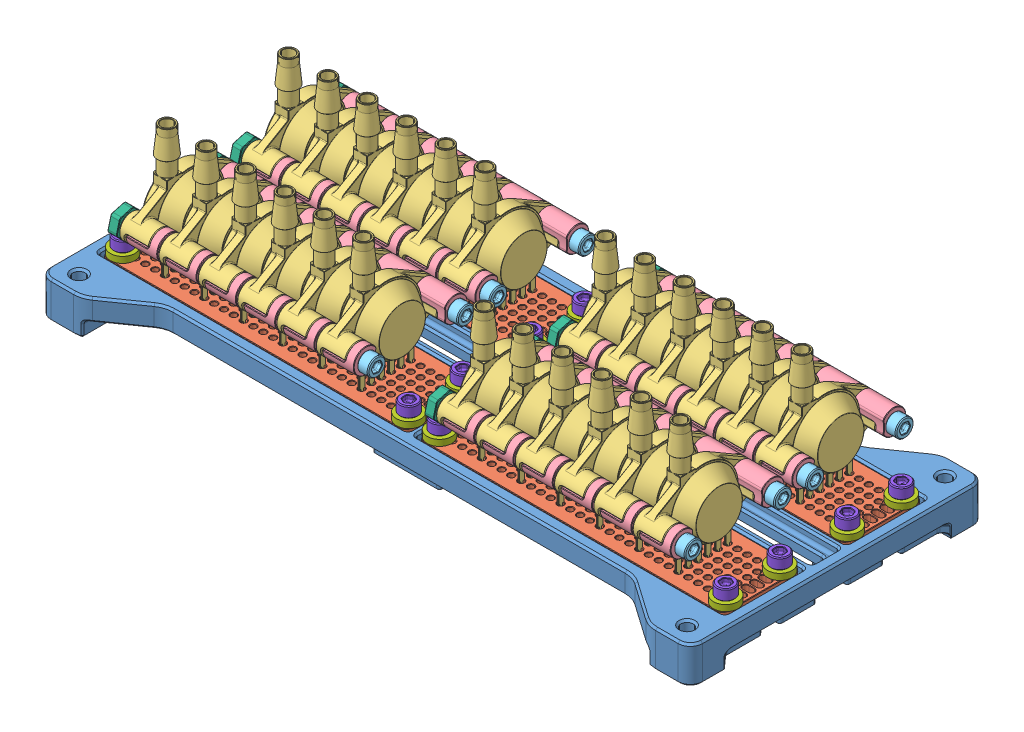
SolidWorks assembly AARL_QR_EL_PM-Pressure_Sensor_Mounting, configuration Default. Lengths in mm.
Overall size (169.39 41.14 76.2).
145 component instances, 8 part files, 124 mates.
Components (placement in the parent):
- AARL_QR_EL_PM_014-1: AARL_QR_EL_PM_014 [Default] at origin size (169.39 9.53 76.2)
- AARL_QR_EL_PA_000-Pressure_Sensor_Array-1: AARL_QR_EL_PA_000-Pressure_Sensor_Array [Default] at (-40.9575 4.1745 15.7163) size (78.74 37.75 32.61)
  - AARL_Puppy_18_03_01_009-1: AARL_Puppy_18_03_01_009 [Default] at origin size (78.74 2 20.32)
  - AARL_Puppy_18_03_01_002-MPX5700GP-1: AARL_Puppy_18_03_01_002-MPX5700GP [Default] at (-30.47 12.9995 0) x (0 0 -1) z (1 0 0) size (29.5 37.75 8.49)
  - AARL_Puppy_18_03_01_002-MPX5700GP-2: AARL_Puppy_18_03_01_002-MPX5700GP [Default] at (-20.31 12.9995 0) x (0 0 -1) z (1 0 0) size (29.5 37.75 8.49)
  - AARL_Puppy_18_03_01_002-MPX5700GP-3: AARL_Puppy_18_03_01_002-MPX5700GP [Default] at (-10.15 12.9995 0) x (0 0 -1) z (1 0 0) size (29.5 37.75 8.49)
  - AARL_Puppy_18_03_01_002-MPX5700GP-4: AARL_Puppy_18_03_01_002-MPX5700GP [Default] at (0.01 12.9995 0) x (0 0 -1) z (1 0 0) size (29.5 37.75 8.49)
  - AARL_Puppy_18_03_01_002-MPX5700GP-5: AARL_Puppy_18_03_01_002-MPX5700GP [Default] at (10.17 12.9995 0) x (0 0 -1) z (1 0 0) size (29.5 37.75 8.49)
  - AARL_Puppy_18_03_01_002-MPX5700GP-6: AARL_Puppy_18_03_01_002-MPX5700GP [Default] at (20.33 12.9995 0) x (0 0 -1) z (1 0 0) size (29.5 37.75 8.49)
  - AARL_Puppy_18_03_01_010-1: AARL_Puppy_18_03_01_010 [Default] at (-20.309 12.9995 11.555) x (0 1 0) z (0 0 1) size (6.35 8.16 5.84)
  - AARL_Puppy_18_03_01_010-2: AARL_Puppy_18_03_01_010 [Default] at (-20.309 12.9995 -11.555) x (0 -1 0) z (0 0 -1) size (6.35 8.16 5.84)
  - AARL_Puppy_18_03_01_010-3: AARL_Puppy_18_03_01_010 [Default] at (-10.149 12.9995 11.555) x (0 1 0) z (0 0 1) size (6.35 8.16 5.84)
  - AARL_Puppy_18_03_01_010-4: AARL_Puppy_18_03_01_010 [Default] at (0.011 12.9995 11.555) x (0 1 0) z (0 0 1) size (6.35 8.16 5.84)
  - AARL_Puppy_18_03_01_010-5: AARL_Puppy_18_03_01_010 [Default] at (10.171 12.9995 11.555) x (0 1 0) z (0 0 1) size (6.35 8.16 5.84)
  - AARL_Puppy_18_03_01_010-6: AARL_Puppy_18_03_01_010 [Default] at (20.331 12.9995 11.555) x (0 1 0) z (0 0 1) size (6.35 8.16 5.84)
  - AARL_Puppy_18_03_01_010-7: AARL_Puppy_18_03_01_010 [Default] at (30.491 12.9995 11.555) x (0 1 0) z (0 0 1) size (6.35 8.16 5.84)
  - AARL_Puppy_18_03_01_010-8: AARL_Puppy_18_03_01_010 [Default] at (-10.1485 12.9995 -11.555) x (0 -1 0) z (0 0 -1) size (6.35 8.16 5.84)
  - AARL_Puppy_18_03_01_010-9: AARL_Puppy_18_03_01_010 [Default] at (0.0115 12.9995 -11.555) x (0 -1 0) z (0 0 -1) size (6.35 8.16 5.84)
  - AARL_Puppy_18_03_01_010-10: AARL_Puppy_18_03_01_010 [Default] at (10.171 12.9995 -11.555) x (0 -1 0) z (0 0 -1) size (6.35 8.16 5.84)
  - AARL_Puppy_18_03_01_010-11: AARL_Puppy_18_03_01_010 [Default] at (20.331 12.9995 -11.555) x (0 -1 0) z (0 0 -1) size (6.35 8.16 5.84)
  - AARL_Puppy_18_03_01_010-12: AARL_Puppy_18_03_01_010 [Default] at (30.491 12.9995 -11.555) x (0 -1 0) z (0 0 -1) size (6.35 8.16 5.84)
  - AARL_Puppy_18_04_01_014-1: AARL_Puppy_18_04_01_014 [Default] at (33.3358 12.9995 11.555) x (0 -0.609481 -0.792801) z (0 0.792801 -0.609481) size (4.65 66.53 4.65)
  - AARL_Puppy_18_04_01_014-2: AARL_Puppy_18_04_01_014 [Default] at (33.3358 12.9995 -11.555) x (0 -0.609481 -0.792801) z (0 0.792801 -0.609481) size (4.65 66.53 4.65)
  - AARL_QR_HW_NU_002-1: AARL_QR_HW_NU_002 [Default] at (-31.6606 12.9995 11.555) x (0 0.703871 0.710328) z (0 -0.710328 0.703871) size (7.09 2.38 6.35)
  - AARL_QR_HW_NU_002-2: AARL_QR_HW_NU_002 [Default] at (-31.6606 12.9995 -11.555) x (0 0.703871 0.710328) z (0 -0.710328 0.703871) size (7.09 2.38 6.35)
- AARL_QR_EL_PA_000-Pressure_Sensor_Array-2: AARL_QR_EL_PA_000-Pressure_Sensor_Array [Default] at (-40.9575 4.1745 -15.7163) size (78.74 37.75 32.61)
  - AARL_Puppy_18_03_01_009-1: AARL_Puppy_18_03_01_009 [Default] at origin size (78.74 2 20.32)
  - AARL_Puppy_18_03_01_002-MPX5700GP-1: AARL_Puppy_18_03_01_002-MPX5700GP [Default] at (-30.47 12.9995 0) x (0 0 -1) z (1 0 0) size (29.5 37.75 8.49)
  - AARL_Puppy_18_03_01_002-MPX5700GP-2: AARL_Puppy_18_03_01_002-MPX5700GP [Default] at (-20.31 12.9995 0) x (0 0 -1) z (1 0 0) size (29.5 37.75 8.49)
  - AARL_Puppy_18_03_01_002-MPX5700GP-3: AARL_Puppy_18_03_01_002-MPX5700GP [Default] at (-10.15 12.9995 0) x (0 0 -1) z (1 0 0) size (29.5 37.75 8.49)
  - AARL_Puppy_18_03_01_002-MPX5700GP-4: AARL_Puppy_18_03_01_002-MPX5700GP [Default] at (0.01 12.9995 0) x (0 0 -1) z (1 0 0) size (29.5 37.75 8.49)
  - AARL_Puppy_18_03_01_002-MPX5700GP-5: AARL_Puppy_18_03_01_002-MPX5700GP [Default] at (10.17 12.9995 0) x (0 0 -1) z (1 0 0) size (29.5 37.75 8.49)
  - AARL_Puppy_18_03_01_002-MPX5700GP-6: AARL_Puppy_18_03_01_002-MPX5700GP [Default] at (20.33 12.9995 0) x (0 0 -1) z (1 0 0) size (29.5 37.75 8.49)
  - AARL_Puppy_18_03_01_010-1: AARL_Puppy_18_03_01_010 [Default] at (-20.309 12.9995 11.555) x (0 1 0) z (0 0 1) size (6.35 8.16 5.84)
  - AARL_Puppy_18_03_01_010-2: AARL_Puppy_18_03_01_010 [Default] at (-20.309 12.9995 -11.555) x (0 -1 0) z (0 0 -1) size (6.35 8.16 5.84)
  - AARL_Puppy_18_03_01_010-3: AARL_Puppy_18_03_01_010 [Default] at (-10.149 12.9995 11.555) x (0 1 0) z (0 0 1) size (6.35 8.16 5.84)
  - AARL_Puppy_18_03_01_010-4: AARL_Puppy_18_03_01_010 [Default] at (0.011 12.9995 11.555) x (0 1 0) z (0 0 1) size (6.35 8.16 5.84)
  - AARL_Puppy_18_03_01_010-5: AARL_Puppy_18_03_01_010 [Default] at (10.171 12.9995 11.555) x (0 1 0) z (0 0 1) size (6.35 8.16 5.84)
  - AARL_Puppy_18_03_01_010-6: AARL_Puppy_18_03_01_010 [Default] at (20.331 12.9995 11.555) x (0 1 0) z (0 0 1) size (6.35 8.16 5.84)
  - AARL_Puppy_18_03_01_010-7: AARL_Puppy_18_03_01_010 [Default] at (30.491 12.9995 11.555) x (0 1 0) z (0 0 1) size (6.35 8.16 5.84)
  - AARL_Puppy_18_03_01_010-8: AARL_Puppy_18_03_01_010 [Default] at (-10.1485 12.9995 -11.555) x (0 -1 0) z (0 0 -1) size (6.35 8.16 5.84)
  - AARL_Puppy_18_03_01_010-9: AARL_Puppy_18_03_01_010 [Default] at (0.0115 12.9995 -11.555) x (0 -1 0) z (0 0 -1) size (6.35 8.16 5.84)
  - AARL_Puppy_18_03_01_010-10: AARL_Puppy_18_03_01_010 [Default] at (10.171 12.9995 -11.555) x (0 -1 0) z (0 0 -1) size (6.35 8.16 5.84)
  - AARL_Puppy_18_03_01_010-11: AARL_Puppy_18_03_01_010 [Default] at (20.331 12.9995 -11.555) x (0 -1 0) z (0 0 -1) size (6.35 8.16 5.84)
  - AARL_Puppy_18_03_01_010-12: AARL_Puppy_18_03_01_010 [Default] at (30.491 12.9995 -11.555) x (0 -1 0) z (0 0 -1) size (6.35 8.16 5.84)
  - AARL_Puppy_18_04_01_014-1: AARL_Puppy_18_04_01_014 [Default] at (33.3358 12.9995 11.555) x (0 -0.609481 -0.792801) z (0 0.792801 -0.609481) size (4.65 66.53 4.65)
  - AARL_Puppy_18_04_01_014-2: AARL_Puppy_18_04_01_014 [Default] at (33.3358 12.9995 -11.555) x (0 -0.609481 -0.792801) z (0 0.792801 -0.609481) size (4.65 66.53 4.65)
  - AARL_QR_HW_NU_002-1: AARL_QR_HW_NU_002 [Default] at (-31.6606 12.9995 11.555) x (0 0.703871 0.710328) z (0 -0.710328 0.703871) size (7.09 2.38 6.35)
  - AARL_QR_HW_NU_002-2: AARL_QR_HW_NU_002 [Default] at (-31.6606 12.9995 -11.555) x (0 0.703871 0.710328) z (0 -0.710328 0.703871) size (7.09 2.38 6.35)
- AARL_QR_EL_PA_000-Pressure_Sensor_Array-3: AARL_QR_EL_PA_000-Pressure_Sensor_Array [Default] at (40.9575 4.1745 15.7163) size (78.74 37.75 32.61)
  - AARL_Puppy_18_03_01_009-1: AARL_Puppy_18_03_01_009 [Default] at origin size (78.74 2 20.32)
  - AARL_Puppy_18_03_01_002-MPX5700GP-1: AARL_Puppy_18_03_01_002-MPX5700GP [Default] at (-30.47 12.9995 0) x (0 0 -1) z (1 0 0) size (29.5 37.75 8.49)
  - AARL_Puppy_18_03_01_002-MPX5700GP-2: AARL_Puppy_18_03_01_002-MPX5700GP [Default] at (-20.31 12.9995 0) x (0 0 -1) z (1 0 0) size (29.5 37.75 8.49)
  - AARL_Puppy_18_03_01_002-MPX5700GP-3: AARL_Puppy_18_03_01_002-MPX5700GP [Default] at (-10.15 12.9995 0) x (0 0 -1) z (1 0 0) size (29.5 37.75 8.49)
  - AARL_Puppy_18_03_01_002-MPX5700GP-4: AARL_Puppy_18_03_01_002-MPX5700GP [Default] at (0.01 12.9995 0) x (0 0 -1) z (1 0 0) size (29.5 37.75 8.49)
  - AARL_Puppy_18_03_01_002-MPX5700GP-5: AARL_Puppy_18_03_01_002-MPX5700GP [Default] at (10.17 12.9995 0) x (0 0 -1) z (1 0 0) size (29.5 37.75 8.49)
  - AARL_Puppy_18_03_01_002-MPX5700GP-6: AARL_Puppy_18_03_01_002-MPX5700GP [Default] at (20.33 12.9995 0) x (0 0 -1) z (1 0 0) size (29.5 37.75 8.49)
  - AARL_Puppy_18_03_01_010-1: AARL_Puppy_18_03_01_010 [Default] at (-20.309 12.9995 11.555) x (0 1 0) z (0 0 1) size (6.35 8.16 5.84)
  - AARL_Puppy_18_03_01_010-2: AARL_Puppy_18_03_01_010 [Default] at (-20.309 12.9995 -11.555) x (0 -1 0) z (0 0 -1) size (6.35 8.16 5.84)
  - AARL_Puppy_18_03_01_010-3: AARL_Puppy_18_03_01_010 [Default] at (-10.149 12.9995 11.555) x (0 1 0) z (0 0 1) size (6.35 8.16 5.84)
  - AARL_Puppy_18_03_01_010-4: AARL_Puppy_18_03_01_010 [Default] at (0.011 12.9995 11.555) x (0 1 0) z (0 0 1) size (6.35 8.16 5.84)
  - AARL_Puppy_18_03_01_010-5: AARL_Puppy_18_03_01_010 [Default] at (10.171 12.9995 11.555) x (0 1 0) z (0 0 1) size (6.35 8.16 5.84)
  - AARL_Puppy_18_03_01_010-6: AARL_Puppy_18_03_01_010 [Default] at (20.331 12.9995 11.555) x (0 1 0) z (0 0 1) size (6.35 8.16 5.84)
  - AARL_Puppy_18_03_01_010-7: AARL_Puppy_18_03_01_010 [Default] at (30.491 12.9995 11.555) x (0 1 0) z (0 0 1) size (6.35 8.16 5.84)
  - AARL_Puppy_18_03_01_010-8: AARL_Puppy_18_03_01_010 [Default] at (-10.1485 12.9995 -11.555) x (0 -1 0) z (0 0 -1) size (6.35 8.16 5.84)
  - AARL_Puppy_18_03_01_010-9: AARL_Puppy_18_03_01_010 [Default] at (0.0115 12.9995 -11.555) x (0 -1 0) z (0 0 -1) size (6.35 8.16 5.84)
  - AARL_Puppy_18_03_01_010-10: AARL_Puppy_18_03_01_010 [Default] at (10.171 12.9995 -11.555) x (0 -1 0) z (0 0 -1) size (6.35 8.16 5.84)
  - AARL_Puppy_18_03_01_010-11: AARL_Puppy_18_03_01_010 [Default] at (20.331 12.9995 -11.555) x (0 -1 0) z (0 0 -1) size (6.35 8.16 5.84)
  - AARL_Puppy_18_03_01_010-12: AARL_Puppy_18_03_01_010 [Default] at (30.491 12.9995 -11.555) x (0 -1 0) z (0 0 -1) size (6.35 8.16 5.84)
  - AARL_Puppy_18_04_01_014-1: AARL_Puppy_18_04_01_014 [Default] at (33.3358 12.9995 11.555) x (0 -0.609481 -0.792801) z (0 0.792801 -0.609481) size (4.65 66.53 4.65)
  - AARL_Puppy_18_04_01_014-2: AARL_Puppy_18_04_01_014 [Default] at (33.3358 12.9995 -11.555) x (0 -0.609481 -0.792801) z (0 0.792801 -0.609481) size (4.65 66.53 4.65)
  - AARL_QR_HW_NU_002-1: AARL_QR_HW_NU_002 [Default] at (-31.6606 12.9995 11.555) x (0 0.703871 0.710328) z (0 -0.710328 0.703871) size (7.09 2.38 6.35)
  - AARL_QR_HW_NU_002-2: AARL_QR_HW_NU_002 [Default] at (-31.6606 12.9995 -11.555) x (0 0.703871 0.710328) z (0 -0.710328 0.703871) size (7.09 2.38 6.35)
- AARL_QR_EL_PA_000-Pressure_Sensor_Array-4: AARL_QR_EL_PA_000-Pressure_Sensor_Array [Default] at (40.9575 4.1745 -15.7163) size (78.74 37.75 32.61)
  - AARL_Puppy_18_03_01_009-1: AARL_Puppy_18_03_01_009 [Default] at origin size (78.74 2 20.32)
  - AARL_Puppy_18_03_01_002-MPX5700GP-1: AARL_Puppy_18_03_01_002-MPX5700GP [Default] at (-30.47 12.9995 0) x (0 0 -1) z (1 0 0) size (29.5 37.75 8.49)
  - AARL_Puppy_18_03_01_002-MPX5700GP-2: AARL_Puppy_18_03_01_002-MPX5700GP [Default] at (-20.31 12.9995 0) x (0 0 -1) z (1 0 0) size (29.5 37.75 8.49)
  - AARL_Puppy_18_03_01_002-MPX5700GP-3: AARL_Puppy_18_03_01_002-MPX5700GP [Default] at (-10.15 12.9995 0) x (0 0 -1) z (1 0 0) size (29.5 37.75 8.49)
  - AARL_Puppy_18_03_01_002-MPX5700GP-4: AARL_Puppy_18_03_01_002-MPX5700GP [Default] at (0.01 12.9995 0) x (0 0 -1) z (1 0 0) size (29.5 37.75 8.49)
  - AARL_Puppy_18_03_01_002-MPX5700GP-5: AARL_Puppy_18_03_01_002-MPX5700GP [Default] at (10.17 12.9995 0) x (0 0 -1) z (1 0 0) size (29.5 37.75 8.49)
  - AARL_Puppy_18_03_01_002-MPX5700GP-6: AARL_Puppy_18_03_01_002-MPX5700GP [Default] at (20.33 12.9995 0) x (0 0 -1) z (1 0 0) size (29.5 37.75 8.49)
  - AARL_Puppy_18_03_01_010-1: AARL_Puppy_18_03_01_010 [Default] at (-20.309 12.9995 11.555) x (0 1 0) z (0 0 1) size (6.35 8.16 5.84)
  - AARL_Puppy_18_03_01_010-2: AARL_Puppy_18_03_01_010 [Default] at (-20.309 12.9995 -11.555) x (0 -1 0) z (0 0 -1) size (6.35 8.16 5.84)
  - AARL_Puppy_18_03_01_010-3: AARL_Puppy_18_03_01_010 [Default] at (-10.149 12.9995 11.555) x (0 1 0) z (0 0 1) size (6.35 8.16 5.84)
  - AARL_Puppy_18_03_01_010-4: AARL_Puppy_18_03_01_010 [Default] at (0.011 12.9995 11.555) x (0 1 0) z (0 0 1) size (6.35 8.16 5.84)
  - AARL_Puppy_18_03_01_010-5: AARL_Puppy_18_03_01_010 [Default] at (10.171 12.9995 11.555) x (0 1 0) z (0 0 1) size (6.35 8.16 5.84)
  - AARL_Puppy_18_03_01_010-6: AARL_Puppy_18_03_01_010 [Default] at (20.331 12.9995 11.555) x (0 1 0) z (0 0 1) size (6.35 8.16 5.84)
  - AARL_Puppy_18_03_01_010-7: AARL_Puppy_18_03_01_010 [Default] at (30.491 12.9995 11.555) x (0 1 0) z (0 0 1) size (6.35 8.16 5.84)
  - AARL_Puppy_18_03_01_010-8: AARL_Puppy_18_03_01_010 [Default] at (-10.1485 12.9995 -11.555) x (0 -1 0) z (0 0 -1) size (6.35 8.16 5.84)
  - AARL_Puppy_18_03_01_010-9: AARL_Puppy_18_03_01_010 [Default] at (0.0115 12.9995 -11.555) x (0 -1 0) z (0 0 -1) size (6.35 8.16 5.84)
  - AARL_Puppy_18_03_01_010-10: AARL_Puppy_18_03_01_010 [Default] at (10.171 12.9995 -11.555) x (0 -1 0) z (0 0 -1) size (6.35 8.16 5.84)
  - AARL_Puppy_18_03_01_010-11: AARL_Puppy_18_03_01_010 [Default] at (20.331 12.9995 -11.555) x (0 -1 0) z (0 0 -1) size (6.35 8.16 5.84)
  - AARL_Puppy_18_03_01_010-12: AARL_Puppy_18_03_01_010 [Default] at (30.491 12.9995 -11.555) x (0 -1 0) z (0 0 -1) size (6.35 8.16 5.84)
  - AARL_Puppy_18_04_01_014-1: AARL_Puppy_18_04_01_014 [Default] at (33.3358 12.9995 11.555) x (0 -0.609481 -0.792801) z (0 0.792801 -0.609481) size (4.65 66.53 4.65)
  - AARL_Puppy_18_04_01_014-2: AARL_Puppy_18_04_01_014 [Default] at (33.3358 12.9995 -11.555) x (0 -0.609481 -0.792801) z (0 0.792801 -0.609481) size (4.65 66.53 4.65)
  - AARL_QR_HW_NU_002-1: AARL_QR_HW_NU_002 [Default] at (-31.6606 12.9995 11.555) x (0 0.703871 0.710328) z (0 -0.710328 0.703871) size (7.09 2.38 6.35)
  - AARL_QR_HW_NU_002-2: AARL_QR_HW_NU_002 [Default] at (-31.6606 12.9995 -11.555) x (0 0.703871 0.710328) z (0 -0.710328 0.703871) size (7.09 2.38 6.35)
- AARL_QR_HW_NU_002-1: AARL_QR_HW_NU_002 [Default] at (77.9462 -1.1906 -22.7012) size (7.09 2.38 6.35)
- AARL_QR_HW_NU_002-2: AARL_QR_HW_NU_002 [Default] at (77.9462 -1.1906 -8.7312) x (0.5 0 -0.866025) z (0.866025 0 0.5) size (7.09 2.38 6.35)
- AARL_QR_HW_NU_002-3: AARL_QR_HW_NU_002 [Default] at (77.9462 -1.1906 8.7312) x (0.5 0 -0.866025) z (0.866025 0 0.5) size (7.09 2.38 6.35)
- AARL_QR_HW_NU_002-4: AARL_QR_HW_NU_002 [Default] at (77.9462 -1.1906 22.7012) x (-0.5 0 -0.866025) z (0.866025 0 -0.5) size (7.09 2.38 6.35)
- AARL_QR_HW_NU_002-5: AARL_QR_HW_NU_002 [Default] at (3.9688 -1.1906 -22.7012) x (-0.5 0 0.866025) z (-0.866025 0 -0.5) size (7.09 2.38 6.35)
- AARL_QR_HW_NU_002-6: AARL_QR_HW_NU_002 [Default] at (-3.9688 -1.1906 -22.7012) x (-0.5 0 0.866025) z (-0.866025 0 -0.5) size (7.09 2.38 6.35)
- AARL_QR_HW_NU_002-7: AARL_QR_HW_NU_002 [Default] at (3.9688 -1.1906 -8.7312) x (-0.5 0 0.866025) z (-0.866025 0 -0.5) size (7.09 2.38 6.35)
- AARL_QR_HW_NU_002-8: AARL_QR_HW_NU_002 [Default] at (-3.9688 -1.1906 -8.7312) x (-0.5 0 0.866025) z (-0.866025 0 -0.5) size (7.09 2.38 6.35)
- AARL_QR_HW_NU_002-9: AARL_QR_HW_NU_002 [Default] at (3.9688 -1.1906 8.7312) x (-0.5 0 0.866025) z (-0.866025 0 -0.5) size (7.09 2.38 6.35)
- AARL_QR_HW_NU_002-10: AARL_QR_HW_NU_002 [Default] at (-3.9688 -1.1906 8.7312) x (-0.5 0 0.866025) z (-0.866025 0 -0.5) size (7.09 2.38 6.35)
- AARL_QR_HW_NU_002-11: AARL_QR_HW_NU_002 [Default] at (3.9688 -1.1906 22.7012) size (7.09 2.38 6.35)
- AARL_QR_HW_NU_002-12: AARL_QR_HW_NU_002 [Default] at (-3.9688 -1.1906 22.7012) size (7.09 2.38 6.35)
- AARL_QR_HW_NU_002-13: AARL_QR_HW_NU_002 [Default] at (-77.9462 -1.1906 22.7012) x (0.5 0 -0.866025) z (0.866025 0 0.5) size (7.09 2.38 6.35)
- AARL_QR_HW_NU_002-14: AARL_QR_HW_NU_002 [Default] at (-77.9462 -1.1906 8.7312) x (0.5 0 -0.866025) z (0.866025 0 0.5) size (7.09 2.38 6.35)
- AARL_QR_HW_NU_002-15: AARL_QR_HW_NU_002 [Default] at (-77.9462 -1.1906 -8.7312) x (0.5 0 -0.866025) z (0.866025 0 0.5) size (7.09 2.38 6.35)
- AARL_QR_HW_NU_002-16: AARL_QR_HW_NU_002 [Default] at (-77.9462 -1.1906 -22.7012) x (0.5 0 -0.866025) z (0.866025 0 0.5) size (7.09 2.38 6.35)
- AARL_QR_HW_WA_002-1: AARL_QR_HW_WA_002 [Default] at (77.9462 5.9677 22.7012) x (0.412963 0 0.910748) z (-0.910748 0 0.412963) size (6.35 1.59 6.35)
- AARL_QR_HW_WA_002-2: AARL_QR_HW_WA_002 [Default] at (3.9688 5.9677 8.7312) x (0.998043 0 0.062526) z (-0.062526 0 0.998043) size (6.35 1.59 6.35)
- AARL_QR_HW_WA_002-3: AARL_QR_HW_WA_002 [Default] at (77.9462 5.9677 8.7312) x (0.253018 0 0.967462) z (-0.967462 0 0.253018) size (6.35 1.59 6.35)
- AARL_QR_HW_WA_002-4: AARL_QR_HW_WA_002 [Default] at (3.9688 5.9677 22.7012) x (0.071525 0 0.997439) z (-0.997439 0 0.071525) size (6.35 1.59 6.35)
- AARL_QR_HW_WA_002-5: AARL_QR_HW_WA_002 [Default] at (-3.9688 5.9677 22.7012) x (0.996603 0 -0.082353) z (0.082353 0 0.996603) size (6.35 1.59 6.35)
- AARL_QR_HW_WA_002-6: AARL_QR_HW_WA_002 [Default] at (-3.9688 5.9677 8.7312) x (0.920537 0 -0.390655) z (0.390655 0 0.920537) size (6.35 1.59 6.35)
- AARL_QR_HW_WA_002-7: AARL_QR_HW_WA_002 [Default] at (-77.9462 5.9677 22.7012) x (-0.982306 0 0.187284) z (-0.187284 0 -0.982306) size (6.35 1.59 6.35)
- AARL_QR_HW_WA_002-8: AARL_QR_HW_WA_002 [Default] at (-77.9462 5.9677 8.7312) x (-0.925221 0 0.379428) z (-0.379428 0 -0.925221) size (6.35 1.59 6.35)
- AARL_QR_HW_WA_002-9: AARL_QR_HW_WA_002 [Default] at (77.9462 5.9677 -8.7312) x (0.923209 0 0.384298) z (-0.384298 0 0.923209) size (6.35 1.59 6.35)
- AARL_QR_HW_WA_002-10: AARL_QR_HW_WA_002 [Default] at (77.9462 5.9677 -22.7012) x (0.906885 0 -0.421379) z (0.421379 0 0.906885) size (6.35 1.59 6.35)
- AARL_QR_HW_WA_002-11: AARL_QR_HW_WA_002 [Default] at (3.9688 5.9677 -8.7312) x (0.666998 0 -0.74506) z (0.74506 0 0.666998) size (6.35 1.59 6.35)
- AARL_QR_HW_WA_002-12: AARL_QR_HW_WA_002 [Default] at (3.9688 5.9677 -22.7012) x (0.41459 0 -0.910008) z (0.910008 0 0.41459) size (6.35 1.59 6.35)
- AARL_QR_HW_WA_002-13: AARL_QR_HW_WA_002 [Default] at (-3.9688 5.9677 -8.7312) x (-0.412721 0 -0.910858) z (0.910858 0 -0.412721) size (6.35 1.59 6.35)
- AARL_QR_HW_WA_002-14: AARL_QR_HW_WA_002 [Default] at (-3.9688 5.9677 -22.7012) x (-0.562919 0 -0.826512) z (0.826512 0 -0.562919) size (6.35 1.59 6.35)
- AARL_QR_HW_WA_002-15: AARL_QR_HW_WA_002 [Default] at (-77.9462 5.9677 -22.7012) x (-0.977148 0 -0.212559) z (0.212559 0 -0.977148) size (6.35 1.59 6.35)
- AARL_QR_HW_WA_002-16: AARL_QR_HW_WA_002 [Default] at (-77.9462 5.9677 -8.7312) x (-0.031489 0 -0.999504) z (0.999504 0 -0.031489) size (6.35 1.59 6.35)
- AARL_QR_HW_CS_033-4-40x0375-1: AARL_QR_HW_CS_033-4-40x0375 [Default] at (77.9462 9.6063 22.7012) x (-0.600005 0 -0.799996) z (-0.799996 0 0.600005) size (4.65 12.55 4.65)
- AARL_QR_HW_CS_033-4-40x0375-2: AARL_QR_HW_CS_033-4-40x0375 [Default] at (77.9462 9.6063 8.7312) x (-0.578893 0 -0.815404) z (-0.815404 0 0.578893) size (4.65 12.55 4.65)
- AARL_QR_HW_CS_033-4-40x0375-3: AARL_QR_HW_CS_033-4-40x0375 [Default] at (3.9688 9.6063 22.7012) x (-0.578893 0 -0.815404) z (-0.815404 0 0.578893) size (4.65 12.55 4.65)
- AARL_QR_HW_CS_033-4-40x0375-4: AARL_QR_HW_CS_033-4-40x0375 [Default] at (3.9688 9.6063 8.7312) x (-0.227923 0 -0.973679) z (-0.973679 0 0.227923) size (4.65 12.55 4.65)
- AARL_QR_HW_CS_033-4-40x0375-5: AARL_QR_HW_CS_033-4-40x0375 [Default] at (-3.9688 9.6063 22.7012) x (-0.578893 0 -0.815404) z (-0.815404 0 0.578893) size (4.65 12.55 4.65)
- AARL_QR_HW_CS_033-4-40x0375-6: AARL_QR_HW_CS_033-4-40x0375 [Default] at (-3.9688 9.6063 8.7312) x (-0.578893 0 -0.815404) z (-0.815404 0 0.578893) size (4.65 12.55 4.65)
- AARL_QR_HW_CS_033-4-40x0375-7: AARL_QR_HW_CS_033-4-40x0375 [Default] at (-77.9462 9.6063 22.7012) x (-0.578893 0 -0.815404) z (-0.815404 0 0.578893) size (4.65 12.55 4.65)
- AARL_QR_HW_CS_033-4-40x0375-8: AARL_QR_HW_CS_033-4-40x0375 [Default] at (-77.9462 9.6063 8.7312) x (-0.578893 0 -0.815404) z (-0.815404 0 0.578893) size (4.65 12.55 4.65)
- AARL_QR_HW_CS_033-4-40x0375-9: AARL_QR_HW_CS_033-4-40x0375 [Default] at (-77.9462 9.6063 -8.7312) x (-0.578893 0 -0.815404) z (-0.815404 0 0.578893) size (4.65 12.55 4.65)
- AARL_QR_HW_CS_033-4-40x0375-10: AARL_QR_HW_CS_033-4-40x0375 [Default] at (-77.9462 9.6063 -22.7012) x (-0.578893 0 -0.815404) z (-0.815404 0 0.578893) size (4.65 12.55 4.65)
- AARL_QR_HW_CS_033-4-40x0375-11: AARL_QR_HW_CS_033-4-40x0375 [Default] at (-3.9688 9.6063 -8.7312) x (-0.578893 0 -0.815404) z (-0.815404 0 0.578893) size (4.65 12.55 4.65)
- AARL_QR_HW_CS_033-4-40x0375-12: AARL_QR_HW_CS_033-4-40x0375 [Default] at (-3.9688 9.6063 -22.7012) x (-0.578893 0 -0.815404) z (-0.815404 0 0.578893) size (4.65 12.55 4.65)
- AARL_QR_HW_CS_033-4-40x0375-13: AARL_QR_HW_CS_033-4-40x0375 [Default] at (3.9688 9.6063 -22.7012) x (-0.782073 0 -0.623187) z (-0.623187 0 0.782073) size (4.65 12.55 4.65)
- AARL_QR_HW_CS_033-4-40x0375-14: AARL_QR_HW_CS_033-4-40x0375 [Default] at (3.9688 9.6063 -8.7312) x (-0.782073 0 -0.623187) z (-0.623187 0 0.782073) size (4.65 12.55 4.65)
- AARL_QR_HW_CS_033-4-40x0375-15: AARL_QR_HW_CS_033-4-40x0375 [Default] at (77.9462 9.6063 -22.7012) x (-0.782073 0 -0.623187) z (-0.623187 0 0.782073) size (4.65 12.55 4.65)
- AARL_QR_HW_CS_033-4-40x0375-16: AARL_QR_HW_CS_033-4-40x0375 [Default] at (77.9462 9.6063 -8.7312) x (-0.782073 0 -0.623187) z (-0.623187 0 0.782073) size (4.65 12.55 4.65)
Mates (geometry in assembly coordinates):
- Concentric1: concentric anti-aligned: cylinder of AARL_QR_EL_PM_014-1 through (-3.9688 5.5572 22.7012) axis (0 -1 0) radius 1.5875; cylinder of AARL_QR_EL_PA_000-Pressure_Sensor_Array-1/AARL_Puppy_18_03_01_009-1 through (-3.9688 3.175 22.7012) axis (0 1 0) radius 1.5
- Concentric2: concentric anti-aligned: cylinder of AARL_QR_EL_PM_014-1 through (-3.9688 5.5572 8.7312) axis (0 -1 0) radius 1.5875; cylinder of AARL_QR_EL_PA_000-Pressure_Sensor_Array-1/AARL_Puppy_18_03_01_009-1 through (-3.9688 3.175 8.7312) axis (0 1 0) radius 1.5
- Coincident1: coincident anti-aligned: plane of AARL_QR_EL_PM_014-1 through (0 3.175 0) normal (0 1 0); plane of AARL_QR_EL_PA_000-Pressure_Sensor_Array-1/AARL_Puppy_18_03_01_009-1 through (-40.9575 3.175 15.7163) normal (0 -1 0)
- Concentric3: concentric anti-aligned: cylinder of AARL_QR_EL_PM_014-1 through (-3.9688 5.5572 -8.7312) axis (0 -1 0) radius 1.5875; cylinder of AARL_QR_EL_PA_000-Pressure_Sensor_Array-2/AARL_Puppy_18_03_01_009-1 through (-3.9688 3.175 -8.7312) axis (0 1 0) radius 1.5
- Concentric4: concentric anti-aligned: cylinder of AARL_QR_EL_PM_014-1 through (-77.9462 5.5572 -22.7012) axis (0 -1 0) radius 1.5875; cylinder of AARL_QR_EL_PA_000-Pressure_Sensor_Array-2/AARL_Puppy_18_03_01_009-1 through (-77.9462 3.175 -22.7012) axis (0 1 0) radius 1.5
- Coincident2: coincident anti-aligned: plane of AARL_QR_EL_PM_014-1 through (0 3.175 0) normal (0 1 0); plane of AARL_QR_EL_PA_000-Pressure_Sensor_Array-2/AARL_Puppy_18_03_01_009-1 through (-40.9575 3.175 -15.7163) normal (0 -1 0)
- Concentric5: concentric anti-aligned: cylinder of AARL_QR_EL_PM_014-1 through (77.9462 5.5572 22.7012) axis (0 -1 0) radius 1.5875; cylinder of AARL_QR_EL_PA_000-Pressure_Sensor_Array-3/AARL_Puppy_18_03_01_009-1 through (77.9462 3.175 22.7012) axis (0 1 0) radius 1.5
- Concentric6: concentric anti-aligned: cylinder of AARL_QR_EL_PM_014-1 through (3.9688 5.5572 8.7312) axis (0 -1 0) radius 1.5875; cylinder of AARL_QR_EL_PA_000-Pressure_Sensor_Array-3/AARL_Puppy_18_03_01_009-1 through (3.9688 3.175 8.7312) axis (0 1 0) radius 1.5
- Coincident3: coincident anti-aligned: plane of AARL_QR_EL_PM_014-1 through (0 3.175 0) normal (0 1 0); plane of AARL_QR_EL_PA_000-Pressure_Sensor_Array-3/AARL_Puppy_18_03_01_009-1 through (40.9575 3.175 15.7163) normal (0 -1 0)
- Concentric7: concentric anti-aligned: cylinder of AARL_QR_EL_PM_014-1 through (77.9462 5.5572 -8.7312) axis (0 -1 0) radius 1.5875; cylinder of AARL_QR_EL_PA_000-Pressure_Sensor_Array-4/AARL_Puppy_18_03_01_009-1 through (77.9462 3.175 -8.7312) axis (0 1 0) radius 1.5
- Concentric8: concentric anti-aligned: cylinder of AARL_QR_EL_PM_014-1 through (3.9688 5.5572 -22.7012) axis (0 -1 0) radius 1.5875; cylinder of AARL_QR_EL_PA_000-Pressure_Sensor_Array-4/AARL_Puppy_18_03_01_009-1 through (3.9688 3.175 -22.7012) axis (0 1 0) radius 1.5
- Coincident4: coincident anti-aligned: plane of AARL_QR_EL_PM_014-1 through (0 3.175 0) normal (0 1 0); plane of AARL_QR_EL_PA_000-Pressure_Sensor_Array-4/AARL_Puppy_18_03_01_009-1 through (40.9575 3.175 -15.7163) normal (0 -1 0)
- Concentric9: concentric anti-aligned: cylinder of AARL_QR_EL_PA_000-Pressure_Sensor_Array-3/AARL_Puppy_18_03_01_009-1 through (77.9462 3.175 22.7012) axis (0 1 0) radius 1.5; cylinder of AARL_QR_HW_WA_002-1 through (77.9462 6.7615 22.7012) axis (0 -1 0) radius 1.5875
- Coincident5: coincident anti-aligned: plane of AARL_QR_EL_PA_000-Pressure_Sensor_Array-3/AARL_Puppy_18_03_01_009-1 through (40.9575 5.174 15.7163) normal (0 1 0); plane of AARL_QR_HW_WA_002-1 through (77.9462 5.174 22.7012) normal (0 -1 0)
- Concentric10: concentric anti-aligned: cylinder of AARL_QR_HW_WA_002-1 through (77.9462 6.7615 22.7012) axis (0 -1 0) radius 1.5875; cylinder of AARL_QR_HW_CS_033-4-40x0375-1 through (77.9462 9.6063 22.7012) axis (0 1 0) radius 1.4224
- Coincident6: coincident anti-aligned: plane of AARL_QR_HW_WA_002-1 through (77.9462 6.7615 22.7012) normal (0 1 0); plane of AARL_QR_HW_CS_033-4-40x0375-1 through (77.0928 6.7615 21.5633) normal (0 -1 0)
- Concentric11: concentric anti-aligned: cylinder of AARL_QR_EL_PA_000-Pressure_Sensor_Array-3/AARL_Puppy_18_03_01_009-1 through (77.9462 3.175 8.7312) axis (0 1 0) radius 1.5; cylinder of AARL_QR_HW_WA_002-3 through (77.9462 6.7615 8.7312) axis (0 -1 0) radius 1.5875
- Coincident7: coincident anti-aligned: plane of AARL_QR_EL_PA_000-Pressure_Sensor_Array-3/AARL_Puppy_18_03_01_009-1 through (40.9575 5.174 15.7163) normal (0 1 0); plane of AARL_QR_HW_WA_002-3 through (77.9462 5.174 8.7312) normal (0 -1 0)
- Concentric12: concentric anti-aligned: cylinder of AARL_QR_EL_PA_000-Pressure_Sensor_Array-3/AARL_Puppy_18_03_01_009-1 through (3.9688 3.175 22.7012) axis (0 1 0) radius 1.5; cylinder of AARL_QR_HW_WA_002-4 through (3.9688 6.7615 22.7012) axis (0 -1 0) radius 1.5875
- Coincident8: coincident anti-aligned: plane of AARL_QR_EL_PA_000-Pressure_Sensor_Array-3/AARL_Puppy_18_03_01_009-1 through (40.9575 5.174 15.7163) normal (0 1 0); plane of AARL_QR_HW_WA_002-4 through (3.9688 5.174 22.7012) normal (0 -1 0)
- Concentric13: concentric anti-aligned: cylinder of AARL_QR_EL_PA_000-Pressure_Sensor_Array-3/AARL_Puppy_18_03_01_009-1 through (3.9688 3.175 8.7312) axis (0 1 0) radius 1.5; cylinder of AARL_QR_HW_WA_002-2 through (3.9688 6.7615 8.7312) axis (0 -1 0) radius 1.5875
- Coincident9: coincident anti-aligned: plane of AARL_QR_EL_PA_000-Pressure_Sensor_Array-3/AARL_Puppy_18_03_01_009-1 through (40.9575 5.174 15.7163) normal (0 1 0); plane of AARL_QR_HW_WA_002-2 through (3.9688 5.174 8.7312) normal (0 -1 0)
- Concentric14: concentric anti-aligned: cylinder of AARL_QR_EL_PA_000-Pressure_Sensor_Array-1/AARL_Puppy_18_03_01_009-1 through (-3.9688 3.175 22.7012) axis (0 1 0) radius 1.5; cylinder of AARL_QR_HW_WA_002-5 through (-3.9688 6.7615 22.7012) axis (0 -1 0) radius 1.5875
- Coincident10: coincident anti-aligned: plane of AARL_QR_EL_PA_000-Pressure_Sensor_Array-1/AARL_Puppy_18_03_01_009-1 through (-40.9575 5.174 15.7163) normal (0 1 0); plane of AARL_QR_HW_WA_002-5 through (-3.9688 5.174 22.7012) normal (0 -1 0)
- Concentric15: concentric anti-aligned: cylinder of AARL_QR_EL_PA_000-Pressure_Sensor_Array-1/AARL_Puppy_18_03_01_009-1 through (-3.9688 3.175 8.7312) axis (0 1 0) radius 1.5; cylinder of AARL_QR_HW_WA_002-6 through (-3.9688 6.7615 8.7312) axis (0 -1 0) radius 1.5875
- Coincident11: coincident anti-aligned: plane of AARL_QR_EL_PA_000-Pressure_Sensor_Array-1/AARL_Puppy_18_03_01_009-1 through (-40.9575 5.174 15.7163) normal (0 1 0); plane of AARL_QR_HW_WA_002-6 through (-3.9688 5.174 8.7312) normal (0 -1 0)
- Concentric16: concentric anti-aligned: cylinder of AARL_QR_EL_PA_000-Pressure_Sensor_Array-1/AARL_Puppy_18_03_01_009-1 through (-77.9462 3.175 22.7012) axis (0 1 0) radius 1.5; cylinder of AARL_QR_HW_WA_002-7 through (-77.9462 6.7615 22.7012) axis (0 -1 0) radius 1.5875
- Coincident12: coincident anti-aligned: plane of AARL_QR_EL_PA_000-Pressure_Sensor_Array-1/AARL_Puppy_18_03_01_009-1 through (-40.9575 5.174 15.7163) normal (0 1 0); plane of AARL_QR_HW_WA_002-7 through (-77.9462 5.174 22.7012) normal (0 -1 0)
- Concentric17: concentric anti-aligned: cylinder of AARL_QR_EL_PA_000-Pressure_Sensor_Array-1/AARL_Puppy_18_03_01_009-1 through (-77.9462 3.175 8.7312) axis (0 1 0) radius 1.5; cylinder of AARL_QR_HW_WA_002-8 through (-77.9462 6.7615 8.7312) axis (0 -1 0) radius 1.5875
- Coincident13: coincident anti-aligned: plane of AARL_QR_EL_PA_000-Pressure_Sensor_Array-1/AARL_Puppy_18_03_01_009-1 through (-40.9575 5.174 15.7163) normal (0 1 0); plane of AARL_QR_HW_WA_002-8 through (-77.9462 5.174 8.7312) normal (0 -1 0)
- Concentric18: concentric anti-aligned: cylinder of AARL_QR_EL_PA_000-Pressure_Sensor_Array-4/AARL_Puppy_18_03_01_009-1 through (77.9462 3.175 -8.7312) axis (0 1 0) radius 1.5; cylinder of AARL_QR_HW_WA_002-9 through (77.9462 6.7615 -8.7312) axis (0 -1 0) radius 1.5875
- Coincident14: coincident anti-aligned: plane of AARL_QR_EL_PA_000-Pressure_Sensor_Array-4/AARL_Puppy_18_03_01_009-1 through (40.9575 5.174 -15.7163) normal (0 1 0); plane of AARL_QR_HW_WA_002-9 through (77.9462 5.174 -8.7312) normal (0 -1 0)
- Concentric19: concentric anti-aligned: cylinder of AARL_QR_EL_PA_000-Pressure_Sensor_Array-4/AARL_Puppy_18_03_01_009-1 through (77.9462 3.175 -22.7012) axis (0 1 0) radius 1.5; cylinder of AARL_QR_HW_WA_002-10 through (77.9462 6.7615 -22.7012) axis (0 -1 0) radius 1.5875
- Coincident15: coincident anti-aligned: plane of AARL_QR_EL_PA_000-Pressure_Sensor_Array-4/AARL_Puppy_18_03_01_009-1 through (40.9575 5.174 -15.7163) normal (0 1 0); plane of AARL_QR_HW_WA_002-10 through (77.9462 5.174 -22.7012) normal (0 -1 0)
- Concentric20: concentric anti-aligned: cylinder of AARL_QR_EL_PA_000-Pressure_Sensor_Array-4/AARL_Puppy_18_03_01_009-1 through (3.9688 3.175 -8.7312) axis (0 1 0) radius 1.5; cylinder of AARL_QR_HW_WA_002-11 through (3.9688 6.7615 -8.7312) axis (0 -1 0) radius 1.5875
- Coincident16: coincident anti-aligned: plane of AARL_QR_EL_PA_000-Pressure_Sensor_Array-4/AARL_Puppy_18_03_01_009-1 through (40.9575 5.174 -15.7163) normal (0 1 0); plane of AARL_QR_HW_WA_002-11 through (3.9688 5.174 -8.7312) normal (0 -1 0)
- Concentric21: concentric anti-aligned: cylinder of AARL_QR_EL_PA_000-Pressure_Sensor_Array-4/AARL_Puppy_18_03_01_009-1 through (3.9688 3.175 -22.7012) axis (0 1 0) radius 1.5; cylinder of AARL_QR_HW_WA_002-12 through (3.9688 6.7615 -22.7012) axis (0 -1 0) radius 1.5875
- Coincident17: coincident anti-aligned: plane of AARL_QR_EL_PA_000-Pressure_Sensor_Array-4/AARL_Puppy_18_03_01_009-1 through (40.9575 5.174 -15.7163) normal (0 1 0); plane of AARL_QR_HW_WA_002-12 through (3.9688 5.174 -22.7012) normal (0 -1 0)
- Concentric22: concentric anti-aligned: cylinder of AARL_QR_EL_PA_000-Pressure_Sensor_Array-2/AARL_Puppy_18_03_01_009-1 through (-3.9688 3.175 -8.7312) axis (0 1 0) radius 1.5; cylinder of AARL_QR_HW_WA_002-13 through (-3.9688 6.7615 -8.7312) axis (0 -1 0) radius 1.5875
- Coincident18: coincident anti-aligned: plane of AARL_QR_EL_PA_000-Pressure_Sensor_Array-2/AARL_Puppy_18_03_01_009-1 through (-40.9575 5.174 -15.7163) normal (0 1 0); plane of AARL_QR_HW_WA_002-13 through (-3.9688 5.174 -8.7312) normal (0 -1 0)
- Concentric23: concentric anti-aligned: cylinder of AARL_QR_EL_PA_000-Pressure_Sensor_Array-2/AARL_Puppy_18_03_01_009-1 through (-3.9688 3.175 -22.7012) axis (0 1 0) radius 1.5; cylinder of AARL_QR_HW_WA_002-14 through (-3.9688 6.7615 -22.7012) axis (0 -1 0) radius 1.5875
- Coincident19: coincident anti-aligned: plane of AARL_QR_EL_PA_000-Pressure_Sensor_Array-2/AARL_Puppy_18_03_01_009-1 through (-40.9575 5.174 -15.7163) normal (0 1 0); plane of AARL_QR_HW_WA_002-14 through (-3.9688 5.174 -22.7012) normal (0 -1 0)
- Concentric24: concentric anti-aligned: cylinder of AARL_QR_EL_PA_000-Pressure_Sensor_Array-2/AARL_Puppy_18_03_01_009-1 through (-77.9462 3.175 -22.7012) axis (0 1 0) radius 1.5; cylinder of AARL_QR_HW_WA_002-15 through (-77.9462 6.7615 -22.7012) axis (0 -1 0) radius 1.5875
- Coincident20: coincident anti-aligned: plane of AARL_QR_EL_PA_000-Pressure_Sensor_Array-2/AARL_Puppy_18_03_01_009-1 through (-40.9575 5.174 -15.7163) normal (0 1 0); plane of AARL_QR_HW_WA_002-15 through (-77.9462 5.174 -22.7012) normal (0 -1 0)
- Concentric25: concentric anti-aligned: cylinder of AARL_QR_EL_PA_000-Pressure_Sensor_Array-2/AARL_Puppy_18_03_01_009-1 through (-77.9462 3.175 -8.7312) axis (0 1 0) radius 1.5; cylinder of AARL_QR_HW_WA_002-16 through (-77.9462 6.7615 -8.7312) axis (0 -1 0) radius 1.5875
- Coincident21: coincident anti-aligned: plane of AARL_QR_EL_PA_000-Pressure_Sensor_Array-2/AARL_Puppy_18_03_01_009-1 through (-40.9575 5.174 -15.7163) normal (0 1 0); plane of AARL_QR_HW_WA_002-16 through (-77.9462 5.174 -8.7312) normal (0 -1 0)
- Concentric26: concentric anti-aligned: cylinder of AARL_QR_HW_WA_002-3 through (77.9462 6.7615 8.7312) axis (0 -1 0) radius 1.5875; cylinder of AARL_QR_HW_CS_033-4-40x0375-2 through (77.9462 9.6063 8.7312) axis (0 1 0) radius 1.4224
- Coincident22: coincident anti-aligned: plane of AARL_QR_HW_WA_002-3 through (77.9462 6.7615 8.7312) normal (0 1 0); plane of AARL_QR_HW_CS_033-4-40x0375-2 through (77.1228 6.7615 7.5714) normal (0 -1 0)
- Concentric27: concentric anti-aligned: cylinder of AARL_QR_HW_WA_002-4 through (3.9688 6.7615 22.7012) axis (0 -1 0) radius 1.5875; cylinder of AARL_QR_HW_CS_033-4-40x0375-3 through (3.9688 9.6063 22.7012) axis (0 1 0) radius 1.4224
- Coincident23: coincident anti-aligned: plane of AARL_QR_HW_WA_002-4 through (3.9688 6.7615 22.7012) normal (0 1 0); plane of AARL_QR_HW_CS_033-4-40x0375-3 through (3.1453 6.7615 21.5414) normal (0 -1 0)
- Concentric28: concentric anti-aligned: cylinder of AARL_QR_HW_WA_002-2 through (3.9688 6.7615 8.7312) axis (0 -1 0) radius 1.5875; cylinder of AARL_QR_HW_CS_033-4-40x0375-4 through (3.9688 9.6063 8.7312) axis (0 1 0) radius 1.4224
- Coincident24: coincident anti-aligned: plane of AARL_QR_HW_WA_002-2 through (3.9688 6.7615 8.7312) normal (0 1 0); plane of AARL_QR_HW_CS_033-4-40x0375-4 through (3.6446 6.7615 7.3463) normal (0 -1 0)
- Concentric29: concentric anti-aligned: cylinder of AARL_QR_HW_WA_002-5 through (-3.9688 6.7615 22.7012) axis (0 -1 0) radius 1.5875; cylinder of AARL_QR_HW_CS_033-4-40x0375-5 through (-3.9688 9.6063 22.7012) axis (0 1 0) radius 1.4224
- Coincident25: coincident anti-aligned: plane of AARL_QR_HW_WA_002-5 through (-3.9688 6.7615 22.7012) normal (0 1 0); plane of AARL_QR_HW_CS_033-4-40x0375-5 through (-4.7922 6.7615 21.5414) normal (0 -1 0)
- Concentric30: concentric anti-aligned: cylinder of AARL_QR_HW_WA_002-6 through (-3.9688 6.7615 8.7312) axis (0 -1 0) radius 1.5875; cylinder of AARL_QR_HW_CS_033-4-40x0375-6 through (-3.9688 9.6063 8.7312) axis (0 1 0) radius 1.4224
- Coincident26: coincident anti-aligned: plane of AARL_QR_HW_WA_002-6 through (-3.9688 6.7615 8.7312) normal (0 1 0); plane of AARL_QR_HW_CS_033-4-40x0375-6 through (-4.7922 6.7615 7.5714) normal (0 -1 0)
- Concentric31: concentric anti-aligned: cylinder of AARL_QR_HW_WA_002-7 through (-77.9462 6.7615 22.7012) axis (0 -1 0) radius 1.5875; cylinder of AARL_QR_HW_CS_033-4-40x0375-7 through (-77.9462 9.6063 22.7012) axis (0 1 0) radius 1.4224
- Coincident27: coincident anti-aligned: plane of AARL_QR_HW_WA_002-7 through (-77.9462 6.7615 22.7012) normal (0 1 0); plane of AARL_QR_HW_CS_033-4-40x0375-7 through (-78.7697 6.7615 21.5414) normal (0 -1 0)
- Concentric32: concentric anti-aligned: cylinder of AARL_QR_HW_WA_002-8 through (-77.9462 6.7615 8.7312) axis (0 -1 0) radius 1.5875; cylinder of AARL_QR_HW_CS_033-4-40x0375-8 through (-77.9462 9.6063 8.7312) axis (0 1 0) radius 1.4224
- Coincident28: coincident anti-aligned: plane of AARL_QR_HW_WA_002-8 through (-77.9462 6.7615 8.7312) normal (0 1 0); plane of AARL_QR_HW_CS_033-4-40x0375-8 through (-78.7697 6.7615 7.5714) normal (0 -1 0)
- Concentric33: concentric anti-aligned: cylinder of AARL_QR_HW_WA_002-16 through (-77.9462 6.7615 -8.7312) axis (0 -1 0) radius 1.5875; cylinder of AARL_QR_HW_CS_033-4-40x0375-9 through (-77.9462 9.6063 -8.7312) axis (0 1 0) radius 1.4224
- Coincident29: coincident anti-aligned: plane of AARL_QR_HW_WA_002-16 through (-77.9462 6.7615 -8.7312) normal (0 1 0); plane of AARL_QR_HW_CS_033-4-40x0375-9 through (-78.7697 6.7615 -9.8911) normal (0 -1 0)
- Concentric34: concentric anti-aligned: cylinder of AARL_QR_HW_WA_002-15 through (-77.9462 6.7615 -22.7012) axis (0 -1 0) radius 1.5875; cylinder of AARL_QR_HW_CS_033-4-40x0375-10 through (-77.9462 9.6063 -22.7012) axis (0 1 0) radius 1.4224
- Coincident30: coincident anti-aligned: plane of AARL_QR_HW_WA_002-15 through (-77.9462 6.7615 -22.7012) normal (0 1 0); plane of AARL_QR_HW_CS_033-4-40x0375-10 through (-78.7697 6.7615 -23.8611) normal (0 -1 0)
- Concentric35: concentric anti-aligned: cylinder of AARL_QR_HW_WA_002-13 through (-3.9688 6.7615 -8.7312) axis (0 -1 0) radius 1.5875; cylinder of AARL_QR_HW_CS_033-4-40x0375-11 through (-3.9688 9.6063 -8.7312) axis (0 1 0) radius 1.4224
- Coincident31: coincident anti-aligned: plane of AARL_QR_HW_WA_002-13 through (-3.9688 6.7615 -8.7312) normal (0 1 0); plane of AARL_QR_HW_CS_033-4-40x0375-11 through (-4.7922 6.7615 -9.8911) normal (0 -1 0)
- Concentric36: concentric anti-aligned: cylinder of AARL_QR_HW_WA_002-14 through (-3.9688 6.7615 -22.7012) axis (0 -1 0) radius 1.5875; cylinder of AARL_QR_HW_CS_033-4-40x0375-12 through (-3.9688 9.6063 -22.7012) axis (0 1 0) radius 1.4224
- Coincident32: coincident anti-aligned: plane of AARL_QR_HW_WA_002-14 through (-3.9688 6.7615 -22.7012) normal (0 1 0); plane of AARL_QR_HW_CS_033-4-40x0375-12 through (-4.7922 6.7615 -23.8611) normal (0 -1 0)
- Concentric37: concentric anti-aligned: cylinder of AARL_QR_HW_WA_002-12 through (3.9688 6.7615 -22.7012) axis (0 -1 0) radius 1.5875; cylinder of AARL_QR_HW_CS_033-4-40x0375-13 through (3.9688 9.6063 -22.7012) axis (0 1 0) radius 1.4224
- Coincident33: coincident anti-aligned: plane of AARL_QR_HW_WA_002-12 through (3.9688 6.7615 -22.7012) normal (0 1 0); plane of AARL_QR_HW_CS_033-4-40x0375-13 through (2.8563 6.7615 -23.5877) normal (0 -1 0)
- Concentric38: concentric anti-aligned: cylinder of AARL_QR_HW_WA_002-11 through (3.9688 6.7615 -8.7312) axis (0 -1 0) radius 1.5875; cylinder of AARL_QR_HW_CS_033-4-40x0375-14 through (3.9688 9.6063 -8.7312) axis (0 1 0) radius 1.4224
- Coincident34: coincident anti-aligned: plane of AARL_QR_HW_WA_002-11 through (3.9688 6.7615 -8.7312) normal (0 1 0); plane of AARL_QR_HW_CS_033-4-40x0375-14 through (2.8563 6.7615 -9.6177) normal (0 -1 0)
- Concentric39: concentric anti-aligned: cylinder of AARL_QR_HW_WA_002-10 through (77.9462 6.7615 -22.7012) axis (0 -1 0) radius 1.5875; cylinder of AARL_QR_HW_CS_033-4-40x0375-15 through (77.9462 9.6063 -22.7012) axis (0 1 0) radius 1.4224
- Coincident35: coincident anti-aligned: plane of AARL_QR_HW_WA_002-10 through (77.9462 6.7615 -22.7012) normal (0 1 0); plane of AARL_QR_HW_CS_033-4-40x0375-15 through (76.8338 6.7615 -23.5877) normal (0 -1 0)
- Concentric40: concentric anti-aligned: cylinder of AARL_QR_HW_WA_002-9 through (77.9462 6.7615 -8.7312) axis (0 -1 0) radius 1.5875; cylinder of AARL_QR_HW_CS_033-4-40x0375-16 through (77.9462 9.6063 -8.7312) axis (0 1 0) radius 1.4224
- Coincident36: coincident anti-aligned: plane of AARL_QR_HW_WA_002-9 through (77.9462 6.7615 -8.7312) normal (0 1 0); plane of AARL_QR_HW_CS_033-4-40x0375-16 through (76.8338 6.7615 -9.6177) normal (0 -1 0)
- Concentric41: concentric aligned: cylinder of AARL_QR_EL_PM_014-1 through (77.9462 5.5572 -22.7012) axis (0 -1 0) radius 1.5875; cylinder of AARL_QR_HW_NU_002-1 through (77.9462 0 -22.7012) axis (0 -1 0) radius 1.4224
- Parallel1: parallel anti-aligned: plane of AARL_QR_EL_PM_014-1 through (79.6327 -2.3813 -19.7802) normal (-0.866025 0 -0.5); plane of AARL_QR_HW_NU_002-1 through (79.7793 0 -19.5262) normal (0.866025 0 0.5)
- Coincident38: coincident anti-aligned: plane of AARL_QR_EL_PM_014-1 through (0 0 0) normal (0 -1 0); plane of AARL_QR_HW_NU_002-1 through (77.9462 0 -22.7012) normal (0 1 0)
- Concentric42: concentric aligned: cylinder of AARL_QR_EL_PM_014-1 through (77.9462 5.5572 -8.7312) axis (0 -1 0) radius 1.5875; cylinder of AARL_QR_HW_NU_002-2 through (77.9462 0 -8.7312) axis (0 -1 0) radius 1.4224
- Parallel2: parallel anti-aligned: plane of AARL_QR_EL_PM_014-1 through (81.3191 -2.3813 -8.7312) normal (-0.866025 0 -0.5); plane of AARL_QR_HW_NU_002-2 through (79.7793 0 -5.5563) normal (0.866025 0 0.5)
- Coincident40: coincident anti-aligned: plane of AARL_QR_EL_PM_014-1 through (0 0 0) normal (0 -1 0); plane of AARL_QR_HW_NU_002-2 through (77.9462 0 -8.7312) normal (0 1 0)
- Concentric43: concentric aligned: cylinder of AARL_QR_EL_PM_014-1 through (77.9462 5.5572 8.7312) axis (0 -1 0) radius 1.5875; cylinder of AARL_QR_HW_NU_002-3 through (77.9462 0 8.7312) axis (0 -1 0) radius 1.4224
- Parallel3: parallel anti-aligned: plane of AARL_QR_EL_PM_014-1 through (79.6327 -2.3813 11.6522) normal (-0.866025 0 -0.5); plane of AARL_QR_HW_NU_002-3 through (79.7793 0 11.9062) normal (0.866025 0 0.5)
- Coincident42: coincident anti-aligned: plane of AARL_QR_EL_PM_014-1 through (0 0 0) normal (0 -1 0); plane of AARL_QR_HW_NU_002-3 through (77.9462 0 8.7312) normal (0 1 0)
- Concentric44: concentric aligned: cylinder of AARL_QR_EL_PM_014-1 through (77.9462 5.5572 22.7012) axis (0 -1 0) radius 1.5875; cylinder of AARL_QR_HW_NU_002-4 through (77.9462 0 22.7012) axis (0 -1 0) radius 1.4224
- Parallel4: parallel anti-aligned: plane of AARL_QR_EL_PM_014-1 through (81.3191 -2.3813 22.7012) normal (-0.866025 0 -0.5); plane of AARL_QR_HW_NU_002-4 through (79.7793 0 25.8762) normal (0.866025 0 0.5)
- Coincident44: coincident anti-aligned: plane of AARL_QR_EL_PM_014-1 through (0 0 0) normal (0 -1 0); plane of AARL_QR_HW_NU_002-4 through (77.9462 0 22.7012) normal (0 1 0)
- Concentric45: concentric aligned: cylinder of AARL_QR_EL_PM_014-1 through (3.9688 5.5572 -22.7012) axis (0 -1 0) radius 1.5875; cylinder of AARL_QR_HW_NU_002-5 through (3.9688 0 -22.7012) axis (0 -1 0) radius 1.4224
- Coincident45: coincident anti-aligned: plane of AARL_QR_EL_PM_014-1 through (0 0 0) normal (0 -1 0); plane of AARL_QR_HW_NU_002-5 through (3.9688 0 -22.7012) normal (0 1 0)
- Parallel5: parallel anti-aligned: plane of AARL_QR_EL_PM_014-1 through (5.6552 -2.3813 -19.7802) normal (-0.866025 0 -0.5); plane of AARL_QR_HW_NU_002-5 through (5.8018 0 -19.5262) normal (0.866025 0 0.5)
- Concentric46: concentric aligned: cylinder of AARL_QR_EL_PM_014-1 through (-3.9688 5.5572 -22.7012) axis (0 -1 0) radius 1.5875; cylinder of AARL_QR_HW_NU_002-6 through (-3.9688 0 -22.7012) axis (0 -1 0) radius 1.4224
- Parallel6: parallel anti-aligned: plane of AARL_QR_EL_PM_014-1 through (-5.6552 -2.3813 -19.7802) normal (0 0 -1); plane of AARL_QR_HW_NU_002-6 through (-5.8018 0 -19.5262) normal (0 0 1)
- Coincident48: coincident anti-aligned: plane of AARL_QR_EL_PM_014-1 through (0 0 0) normal (0 -1 0); plane of AARL_QR_HW_NU_002-6 through (-3.9688 0 -22.7012) normal (0 1 0)
- Concentric47: concentric aligned: cylinder of AARL_QR_EL_PM_014-1 through (3.9688 5.5572 -8.7312) axis (0 -1 0) radius 1.5875; cylinder of AARL_QR_HW_NU_002-7 through (3.9688 0 -8.7312) axis (0 -1 0) radius 1.4224
- Parallel7: parallel anti-aligned: plane of AARL_QR_EL_PM_014-1 through (5.6552 -2.3813 -5.8102) normal (0 0 -1); plane of AARL_QR_HW_NU_002-7 through (2.1357 0 -5.5563) normal (0 0 1)
- Coincident50: coincident anti-aligned: plane of AARL_QR_EL_PM_014-1 through (0 0 0) normal (0 -1 0); plane of AARL_QR_HW_NU_002-7 through (3.9688 0 -8.7312) normal (0 1 0)
- Concentric48: concentric aligned: cylinder of AARL_QR_EL_PM_014-1 through (-3.9688 5.5572 -8.7312) axis (0 -1 0) radius 1.5875; cylinder of AARL_QR_HW_NU_002-8 through (-3.9688 0 -8.7312) axis (0 -1 0) radius 1.4224
- Parallel8: parallel anti-aligned: plane of AARL_QR_EL_PM_014-1 through (-5.6552 -2.3813 -5.8102) normal (0.866025 0 -0.5); plane of AARL_QR_HW_NU_002-8 through (-7.6349 0 -8.7312) normal (-0.866025 0 0.5)
- Coincident52: coincident anti-aligned: plane of AARL_QR_EL_PM_014-1 through (0 0 0) normal (0 -1 0); plane of AARL_QR_HW_NU_002-8 through (-3.9688 0 -8.7312) normal (0 1 0)
- Concentric49: concentric aligned: cylinder of AARL_QR_EL_PM_014-1 through (3.9688 5.5572 8.7312) axis (0 -1 0) radius 1.5875; cylinder of AARL_QR_HW_NU_002-9 through (3.9688 0 8.7312) axis (0 -1 0) radius 1.4224
- Parallel9: parallel anti-aligned: plane of AARL_QR_EL_PM_014-1 through (5.6552 -2.3813 5.8102) normal (0 0 1); plane of AARL_QR_HW_NU_002-9 through (5.8018 0 5.5563) normal (0 0 -1)
- Coincident54: coincident anti-aligned: plane of AARL_QR_EL_PM_014-1 through (0 0 0) normal (0 -1 0); plane of AARL_QR_HW_NU_002-9 through (3.9688 0 8.7312) normal (0 1 0)
- Concentric50: concentric aligned: cylinder of AARL_QR_EL_PM_014-1 through (-3.9688 5.5572 8.7312) axis (0 -1 0) radius 1.5875; cylinder of AARL_QR_HW_NU_002-10 through (-3.9688 0 8.7312) axis (0 -1 0) radius 1.4224
- Parallel10: parallel anti-aligned: plane of AARL_QR_EL_PM_014-1 through (-5.6552 -2.3813 11.6522) normal (0 0 -1); plane of AARL_QR_HW_NU_002-10 through (-5.8018 0 11.9062) normal (0 0 1)
- Coincident56: coincident anti-aligned: plane of AARL_QR_EL_PM_014-1 through (0 0 0) normal (0 -1 0); plane of AARL_QR_HW_NU_002-10 through (-3.9688 0 8.7312) normal (0 1 0)
- Concentric51: concentric aligned: cylinder of AARL_QR_EL_PM_014-1 through (3.9688 5.5572 22.7012) axis (0 -1 0) radius 1.5875; cylinder of AARL_QR_HW_NU_002-11 through (3.9688 0 22.7012) axis (0 -1 0) radius 1.4224
- Coincident57: coincident anti-aligned: plane of AARL_QR_EL_PM_014-1 through (0 0 0) normal (0 -1 0); plane of AARL_QR_HW_NU_002-11 through (3.9688 0 22.7012) normal (0 1 0)
- Parallel11: parallel anti-aligned: plane of AARL_QR_EL_PM_014-1 through (2.2823 -2.3813 19.7802) normal (0 0 1); plane of AARL_QR_HW_NU_002-11 through (5.8018 0 19.5262) normal (0 0 -1)
- Concentric52: concentric aligned: cylinder of AARL_QR_EL_PM_014-1 through (-3.9688 5.5572 22.7012) axis (0 -1 0) radius 1.5875; cylinder of AARL_QR_HW_NU_002-12 through (-3.9688 0 22.7012) axis (0 -1 0) radius 1.4224
- Parallel12: parallel anti-aligned: plane of AARL_QR_EL_PM_014-1 through (-1.5124 -2.3813 24.2888) normal (-0.866025 0 -0.5); plane of AARL_QR_HW_NU_002-12 through (-2.1357 0 25.8762) normal (0.866025 0 0.5)
- Coincident60: coincident anti-aligned: plane of AARL_QR_EL_PM_014-1 through (0 0 0) normal (0 -1 0); plane of AARL_QR_HW_NU_002-12 through (-3.9688 0 22.7012) normal (0 1 0)
- Concentric53: concentric aligned: cylinder of AARL_QR_EL_PM_014-1 through (-77.9462 5.5572 22.7012) axis (0 -1 0) radius 1.5875; cylinder of AARL_QR_HW_NU_002-13 through (-77.9462 0 22.7012) axis (0 -1 0) radius 1.4224
- Parallel13: parallel anti-aligned: plane of AARL_QR_EL_PM_014-1 through (-79.6327 -2.3813 25.6222) normal (0 0 -1); plane of AARL_QR_HW_NU_002-13 through (-79.7793 0 25.8762) normal (0 0 1)
- Coincident62: coincident anti-aligned: plane of AARL_QR_EL_PM_014-1 through (0 0 0) normal (0 -1 0); plane of AARL_QR_HW_NU_002-13 through (-77.9462 0 22.7012) normal (0 1 0)
- Concentric54: concentric aligned: cylinder of AARL_QR_EL_PM_014-1 through (-77.9462 5.5572 8.7312) axis (0 -1 0) radius 1.5875; cylinder of AARL_QR_HW_NU_002-14 through (-77.9462 0 8.7312) axis (0 -1 0) radius 1.4224
- Parallel14: parallel anti-aligned: plane of AARL_QR_EL_PM_014-1 through (-79.6327 -2.3813 11.6522) normal (0.866025 0 -0.5); plane of AARL_QR_HW_NU_002-14 through (-81.6124 0 8.7312) normal (-0.866025 0 0.5)
- Coincident64: coincident anti-aligned: plane of AARL_QR_EL_PM_014-1 through (0 0 0) normal (0 -1 0); plane of AARL_QR_HW_NU_002-14 through (-77.9462 0 8.7312) normal (0 1 0)
- Concentric55: concentric aligned: cylinder of AARL_QR_EL_PM_014-1 through (-77.9462 5.5572 -8.7312) axis (0 -1 0) radius 1.5875; cylinder of AARL_QR_HW_NU_002-15 through (-77.9462 0 -8.7312) axis (0 -1 0) radius 1.4224
- Parallel15: parallel anti-aligned: plane of AARL_QR_EL_PM_014-1 through (-81.3191 -2.3813 -8.7312) normal (0.866025 0 -0.5); plane of AARL_QR_HW_NU_002-15 through (-81.6124 0 -8.7312) normal (-0.866025 0 0.5)
- Coincident66: coincident anti-aligned: plane of AARL_QR_EL_PM_014-1 through (0 0 0) normal (0 -1 0); plane of AARL_QR_HW_NU_002-15 through (-77.9462 0 -8.7312) normal (0 1 0)
- Concentric56: concentric aligned: cylinder of AARL_QR_EL_PM_014-1 through (-77.9462 5.5572 -22.7012) axis (0 -1 0) radius 1.5875; cylinder of AARL_QR_HW_NU_002-16 through (-77.9462 0 -22.7012) axis (0 -1 0) radius 1.4224
- Parallel16: parallel anti-aligned: plane of AARL_QR_EL_PM_014-1 through (-79.6327 -2.3813 -19.7802) normal (0.866025 0 -0.5); plane of AARL_QR_HW_NU_002-16 through (-81.6124 0 -22.7012) normal (-0.866025 0 0.5)
- Coincident68: coincident anti-aligned: plane of AARL_QR_EL_PM_014-1 through (0 0 0) normal (0 -1 0); plane of AARL_QR_HW_NU_002-16 through (-77.9462 0 -22.7012) normal (0 1 0)
